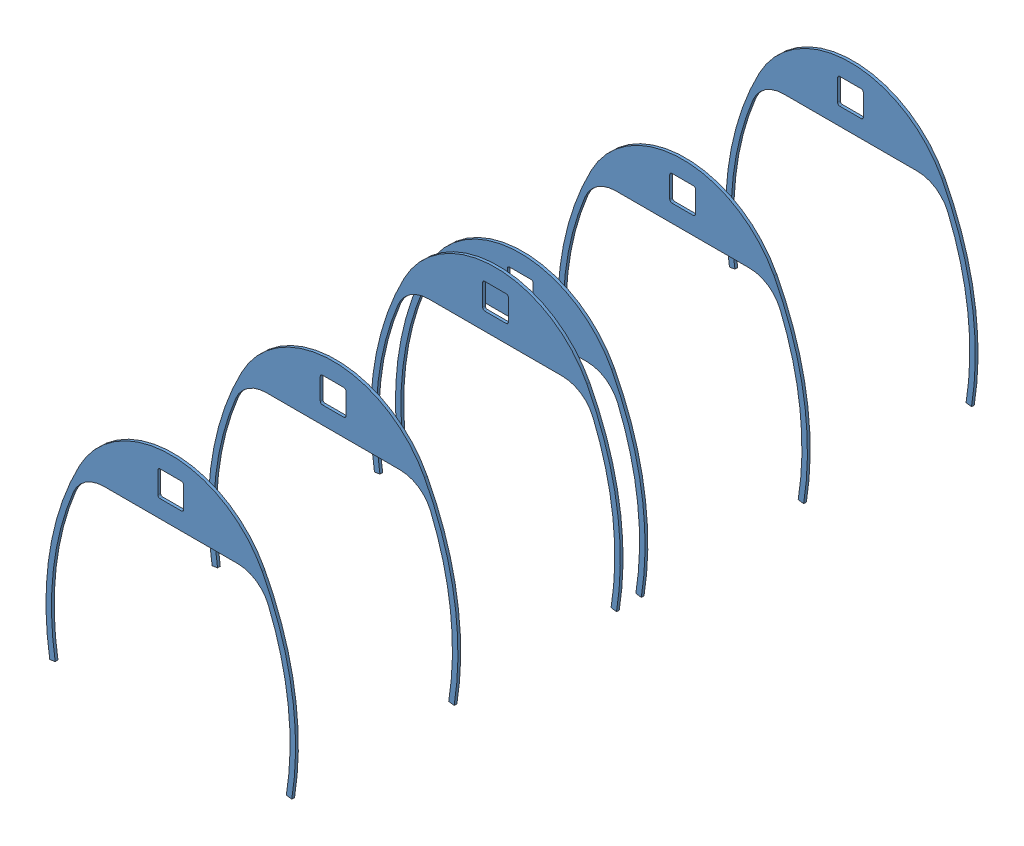
SolidWorks assembly Assem6, configuration Default. Lengths in mm.
Overall size (288.01 274.33 787.4).
6 component instances, 1 part files, 15 mates.
Components (placement in the parent):
- Rib_Fuselage-1: Rib_Fuselage [Default] at origin size (288.01 274.33 3.17)
- Rib_Fuselage-2: Rib_Fuselage [Default] at (0 0 -187.325) size (288.01 274.33 3.17)
- Rib_Fuselage-3: Rib_Fuselage [Default] at (0 0 -374.65) size (288.01 274.33 3.17)
- Rib_Fuselage-5: Rib_Fuselage [Default] at (0 0 -403.225) size (288.01 274.33 3.17)
- Rib_Fuselage-7: Rib_Fuselage [Default] at (0 0 -590.55) size (288.01 274.33 3.17)
- Rib_Fuselage-9: Rib_Fuselage [Default] at (0 0 -784.225) size (288.01 274.33 3.17)
Mates (geometry in assembly coordinates):
- Coincident1: coincident aligned: plane of Rib_Fuselage-1 through (-14.859 223.3951 -0.001) normal (0 1 0); plane of Rib_Fuselage-2 through (-14.859 223.3951 -187.326) normal (0 1 0)
- Coincident2: coincident aligned: plane of Rib_Fuselage-1 through (-14.859 253.1131 -0.001) normal (1 0 0); plane of Rib_Fuselage-2 through (-14.859 253.1131 -187.326) normal (1 0 0)
- Distance1: distance = 184.15 mm anti-aligned: plane of Rib_Fuselage-2 through (0 0 -184.15) normal (0 0 1); plane of Rib_Fuselage-1 through (0 0 0) normal (0 0 -1)
- Coincident4: coincident aligned: plane of Rib_Fuselage-2 through (-14.859 223.3951 -187.326) normal (0 1 0); plane of Rib_Fuselage-3 through (-14.859 223.3951 -374.651) normal (0 1 0)
- Coincident5: coincident aligned: plane of Rib_Fuselage-2 through (-14.859 253.1131 -187.326) normal (1 0 0); plane of Rib_Fuselage-3 through (-14.859 253.1131 -374.651) normal (1 0 0)
- Distance2: distance = 184.15 mm anti-aligned: plane of Rib_Fuselage-3 through (0 0 -371.475) normal (0 0 1); plane of Rib_Fuselage-2 through (0 0 -187.325) normal (0 0 -1)
- Coincident6: coincident aligned: plane of Rib_Fuselage-3 through (-14.859 223.3951 -374.651) normal (0 1 0); plane of Rib_Fuselage-5 through (-14.859 223.3951 -403.226) normal (0 1 0)
- Coincident7: coincident aligned: plane of Rib_Fuselage-3 through (-14.859 253.1131 -374.651) normal (1 0 0); plane of Rib_Fuselage-5 through (-14.859 253.1131 -403.226) normal (1 0 0)
- Distance3: distance = 25.4 mm anti-aligned: plane of Rib_Fuselage-5 through (0 0 -400.05) normal (0 0 1); plane of Rib_Fuselage-3 through (0 0 -374.65) normal (0 0 -1)
- Coincident8: coincident aligned: plane of Rib_Fuselage-5 through (-14.859 223.3951 -403.226) normal (0 1 0); plane of Rib_Fuselage-7 through (-14.859 223.3951 -590.551) normal (0 1 0)
- Coincident9: coincident aligned: plane of Rib_Fuselage-5 through (-14.859 253.1131 -403.226) normal (1 0 0); plane of Rib_Fuselage-7 through (-14.859 253.1131 -590.551) normal (1 0 0)
- Distance4: distance = 184.15 mm anti-aligned: plane of Rib_Fuselage-7 through (0 0 -587.375) normal (0 0 1); plane of Rib_Fuselage-5 through (0 0 -403.225) normal (0 0 -1)
- Coincident10: coincident aligned: plane of Rib_Fuselage-7 through (-14.859 223.3951 -590.551) normal (0 1 0); plane of Rib_Fuselage-9 through (-14.859 223.3951 -784.226) normal (0 1 0)
- Coincident11: coincident aligned: plane of Rib_Fuselage-7 through (-14.859 253.1131 -590.551) normal (1 0 0); plane of Rib_Fuselage-9 through (-14.859 253.1131 -784.226) normal (1 0 0)
- Distance5: distance = 190.5 mm anti-aligned: plane of Rib_Fuselage-9 through (0 0 -781.05) normal (0 0 1); plane of Rib_Fuselage-7 through (0 0 -590.55) normal (0 0 -1)
